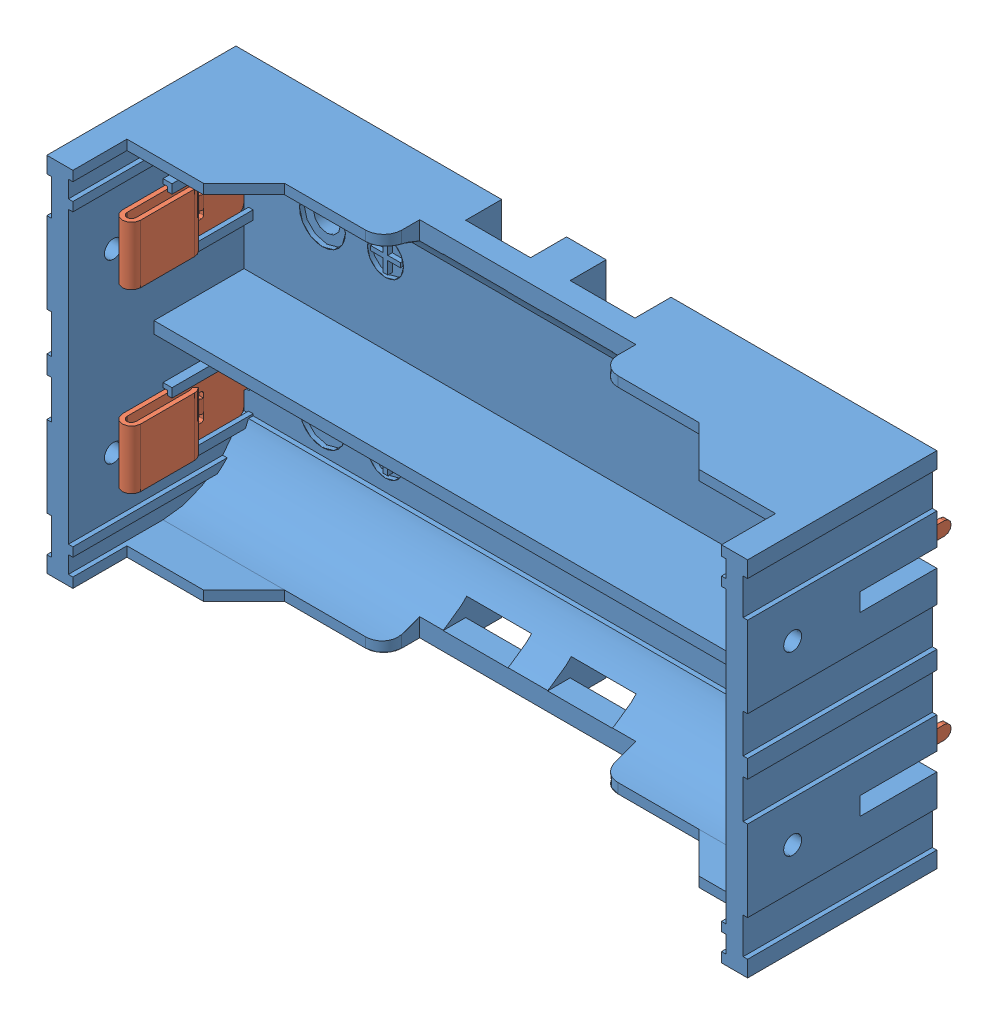
SolidWorks assembly KLS5-18650-002-D, configuration По умолчанию. Lengths in mm.
Overall size (77.8 40.2 25).
5 component instances, 2 part files, 0 mates.
Components (placement in the parent):
- KLS5-18650-002-D_Plastic-1: KLS5-18650-002-D_Plastic [По умолчанию] at origin size (77.8 40.2 21.4)
- KLS5-18650-002-D_Me-1: KLS5-18650-002-D_Me [По умолчанию] at (-36.5 6.55 -4) x (-1 0 0) z (0 1 0) size (3.41 20 6.5)
- KLS5-18650-002-D_Me-2: KLS5-18650-002-D_Me [По умолчанию] at (36.5 13.05 -4) x (1 0 0) z (0 -1 0) size (3.41 20 6.5)
- KLS5-18650-002-D_Me-3: KLS5-18650-002-D_Me [По умолчанию] at (-36.5 -13.05 -4) x (-1 0 0) z (0 1 0) size (3.41 20 6.5)
- KLS5-18650-002-D_Me-4: KLS5-18650-002-D_Me [По умолчанию] at (36.5 -6.55 -4) x (1 0 0) z (0 -1 0) size (3.41 20 6.5)
